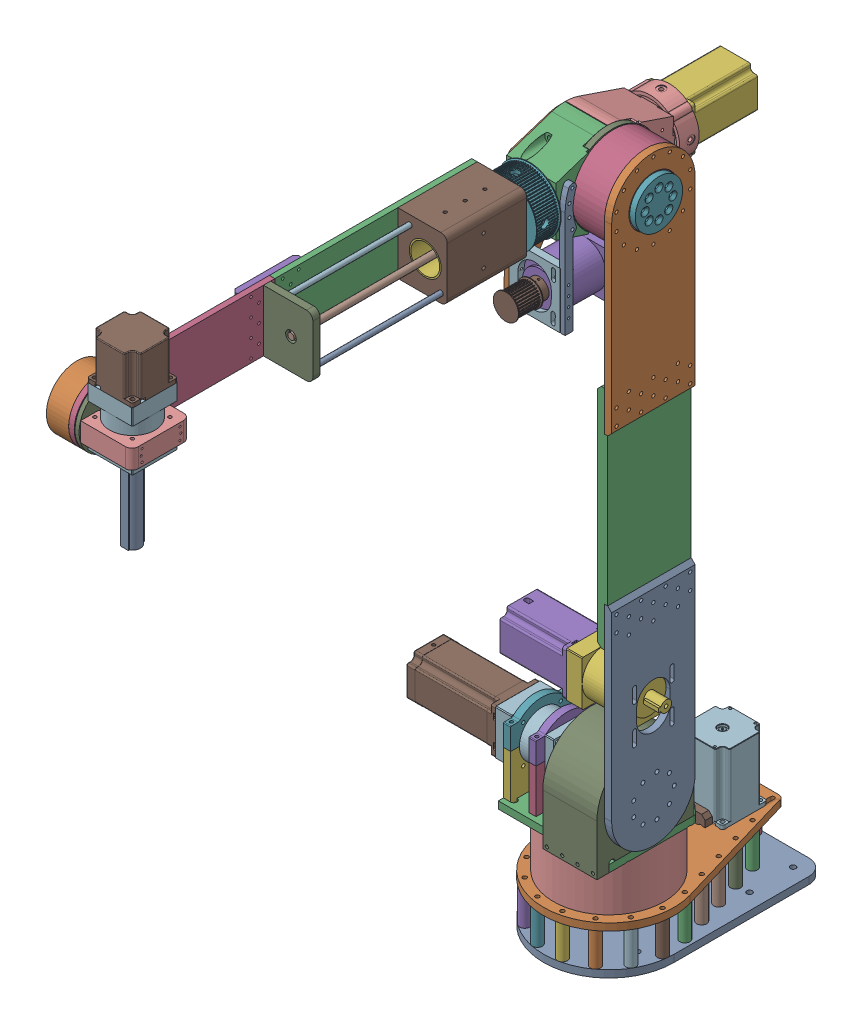
SolidWorks assembly arm_manipulator_part_assembly, configuration Default. Lengths in mm.
Overall size (298.53 944.04 826.78).
7 component instances, 7 part files, 14 mates.
Components (placement in the parent):
- arm_manipulator_base-2: arm_manipulator_base [Default] at (202.1937 277.6975 -479.8461) size (164 143 271.64)
- arm_manipulator_link_1-2: arm_manipulator_link_1 [Default] at (259.0017 292.4687 -8.2507) size (275.53 207 154)
- arm_manipulator_link_2-2: arm_manipulator_link_2 [Default] at (-183.2735 240.0194 -16.7507) size (181 755 105)
- arm_manipulator_link_3-2: arm_manipulator_link_3 [Default] at (-176.2735 481.6566 36.5704) x (1 0 0) z (0 0.008104 0.999967) size (124.88 186.53 180.44)
- arm_manipulator_link_4-2: arm_manipulator_link_4 [Default] at (-231.8992 565.3697 -252.7532) size (109.28 79.36 796.55)
- arm_manipulator_link_5-2: arm_manipulator_link_5 [Default] at (-227.1485 565.96 469.3048) x (1 0 0) z (0 -1 0) size (111.23 77 151)
- Toolframe-2: Toolframe [Default] at (-263.1485 586.96 505.8869) x (1 0 0) z (0 0 -1) size (20 100 20) (hidden)
Mates (geometry in assembly coordinates):
- Concentric1: concentric aligned: cylinder of arm_manipulator_base-2 through (-262.7735 -101.0832 -92.7507) axis (0 -1 0) radius 62.49; cylinder of arm_manipulator_link_1-2 through (-262.7735 -99.0832 -92.7507) axis (0 -1 0) radius 40.01
- Concentric2: concentric anti-aligned: cylinder of arm_manipulator_link_1-2 through (-263.2735 -37.0832 -69.2507) axis (1 0 0) radius 32.51; cylinder of arm_manipulator_link_2-2 through (-190.2735 -37.0832 -69.2507) axis (-1 0 0) radius 32.56
- Coincident2: coincident anti-aligned: plane of arm_manipulator_link_2-2 through (-190.2735 287.9168 -69.2507) normal (-1 0 0); plane of arm_manipulator_link_1-2 through (-190.2735 -37.0832 -69.2507) normal (1 0 0)
- Concentric3: concentric aligned: cylinder of arm_manipulator_link_2-2 through (-192.2735 612.9168 -69.2507) axis (-1 0 0) radius 52.5; cylinder of arm_manipulator_link_3-2 through (-182.6485 612.9168 -69.2507) axis (-1 0 0) radius 22.51
- Coincident3: coincident anti-aligned: plane of arm_manipulator_link_2-2 through (-183.2735 287.9168 -69.2507) normal (1 0 0); plane of arm_manipulator_link_3-2 through (-183.2735 612.9168 -69.2507) normal (-1 0 0)
- Concentric5: concentric anti-aligned: circle of arm_manipulator_link_4-2; cylinder of arm_manipulator_link_5-2 through (-334.1235 612.96 505.8869) axis (1 0 0) radius 15.01
- Concentric6: concentric anti-aligned: cylinder of arm_manipulator_link_5-2 through (-263.1485 586.96 505.8869) axis (0 -1 0) radius 7; cylinder of Toolframe-2 through (-263.1485 486.96 505.8869) axis (0 1 0) radius 7
- Coincident12: coincident anti-aligned: plane of arm_manipulator_link_5-2 through (-263.1485 586.96 505.8869) normal (0 -1 0); plane of Toolframe-2 through (-263.1485 586.96 505.8869) normal (0 1 0)
- Coincident14: coincident anti-aligned: plane of arm_manipulator_base-2 through (-262.7735 -101.0832 -92.7507) normal (0 1 0); plane of arm_manipulator_link_1-2 through (-262.7735 -101.0832 -92.7507) normal (0 -1 0)
- Concentric7: concentric aligned: cylinder of arm_manipulator_link_3-2 through (-263.1485 612.96 4.4369) axis (0 0 -1) radius 21; cylinder of arm_manipulator_link_4-2 through (-263.1485 612.96 137.6369) axis (0 0 -1) radius 20.01
- Coincident15: coincident anti-aligned: plane of arm_manipulator_link_3-2; plane of arm_manipulator_link_4-2
- Coincident16: coincident anti-aligned: plane of arm_manipulator_link_5-2 through (-297.7485 612.96 505.8869) normal (-1 0 0); plane of arm_manipulator_link_4-2 through (-297.7485 612.96 291.0119) normal (1 0 0)
- Parallel1: parallel aligned: plane of arm_manipulator_base-2 through (-263.1235 -84.0832 -235.9607) normal (0 1 0); plane of arm_manipulator_link_5-2 through (-289.6485 716.96 489.3169) normal (0 1 0)
- Parallel2: parallel aligned: plane of arm_manipulator_base-2 through (-263.1235 -163.3288 -264.1607) normal (0 0 -1); plane of arm_manipulator_link_5-2 through (-291.6485 738.96 477.3869) normal (0 0 -1)
